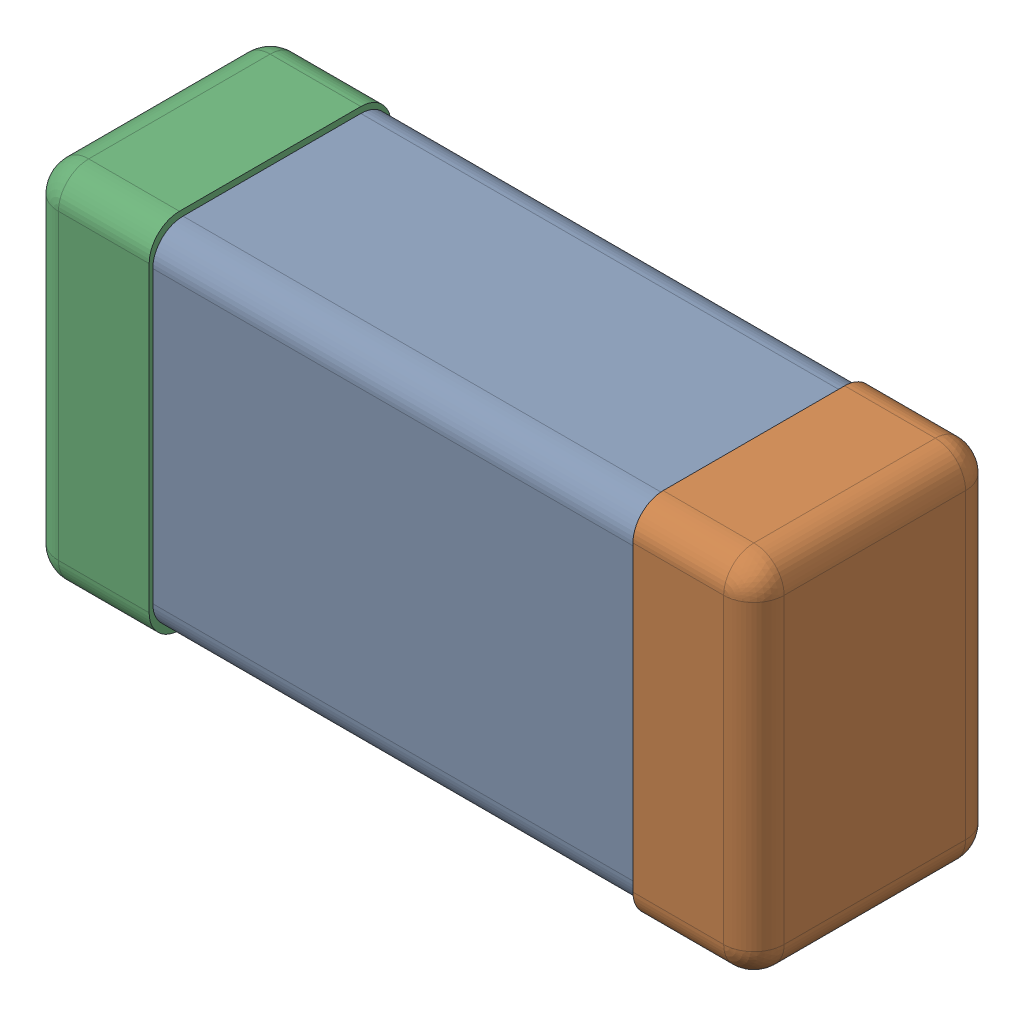
SolidWorks assembly C0201_020_34, configuration Standard. Lengths in mm.
Overall size (0.6 0.3 0.2).
4 component instances, 3 part files, 0 mates.
Components (placement in the parent):
- C0201_020_35-1: C0201_020_35 [Standard] at origin size (0.6 0.3 0.2)
  - Part 3_2-1: Part 3_2 [Standard] at (0 0 -7.3015) size (0.5 0.29 0.2)
  - Part 2_2-1: Part 2_2 [Standard] at (0 0 -7.3) size (0.1 0.3 0.2)
  - Part 1_2-1: Part 1_2 [Standard] at (0 0 -7.3) size (0.1 0.3 0.2)
